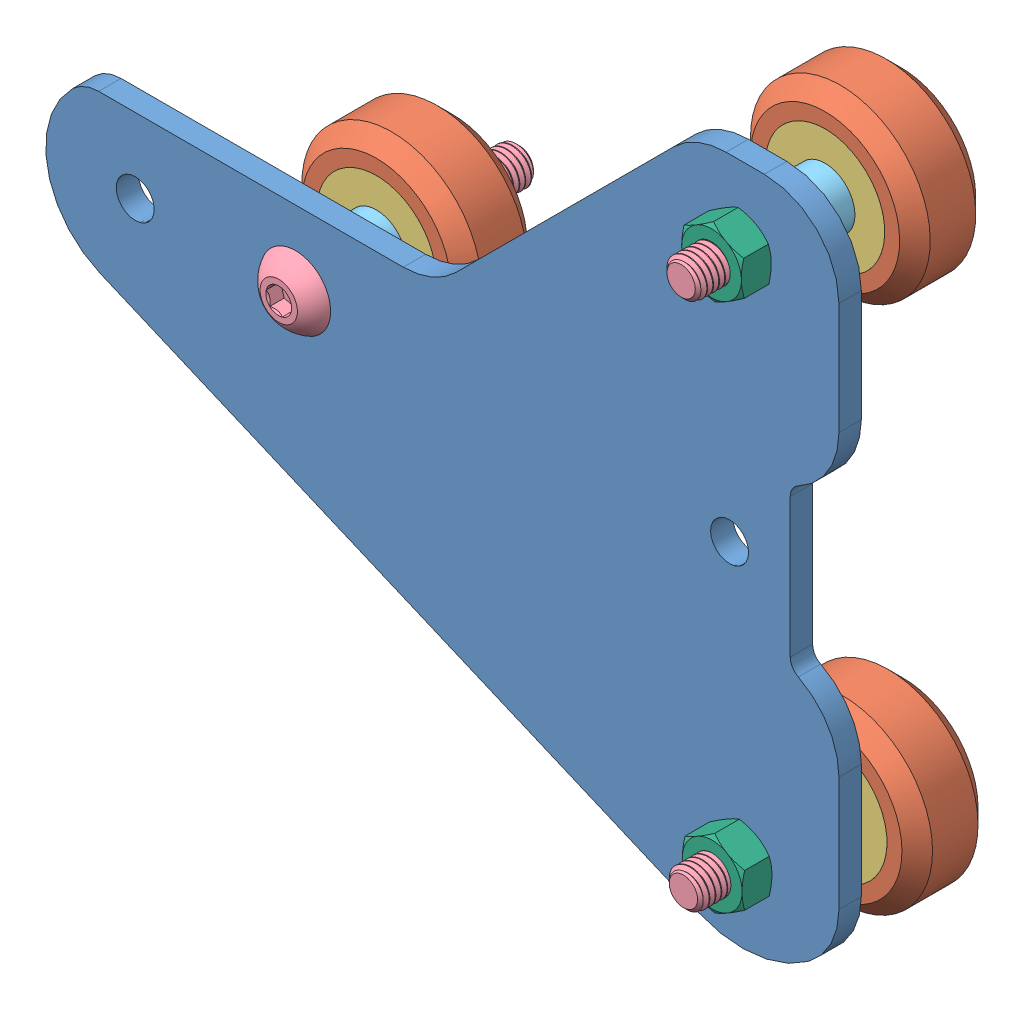
SolidWorks assembly Assembled_Z-Stent, configuration Default. Lengths in mm.
Overall size (110.68 104.98 29.88).
22 component instances, 6 part files, 8 mates.
Components (placement in the parent):
- Z Stent-2: Z Stent [Default] at origin size (106.35 91.34 3)
- roller_screw_assembly-1: roller_screw_assembly [Default] at (46.2218 63.5944 -12.95) x (0.760075 -0.649836 0) z (0 0 -1) size (24.1 24.1 20.97)
  - roller_rubber-1: roller_rubber [Default] at origin size (24.1 24.1 10.2)
  - Bearing for Roller-1: Bearing for Roller [Default] at (0 0 3.1) x (0.970422 -0.241413 0) z (0 0 1) size (16 16 2)
  - Bearing for Roller-2: Bearing for Roller [Default] at (0 0 -5.1) x (0.995973 0.089651 0) z (0 0 1) size (16 16 2)
  - 92095A211_Button Head Hex Drive Screw-1: 92095A211_Button Head Hex Drive Screw [92095A211] at (0 0 7.85) x (-0.966026 0.258445 0) z (0 0 1) size (9.5 9.5 17.99)
  - Roller Spacer-1: Roller Spacer [short] at (0 0 -12.95) x (0.816952 -0.576706 0) z (0 0 1) size (8 8 7.85)
- roller_screw_assembly-2: roller_screw_assembly [Default] at (46.2646 -7.409 -13.2145) x (0.760075 -0.649836 0) z (0 0 -1) size (24.1 24.1 20.97)
  - roller_rubber-1: roller_rubber [Default] at origin size (24.1 24.1 10.2)
  - Bearing for Roller-1: Bearing for Roller [Default] at (0 0 3.1) x (0.970422 -0.241413 0) z (0 0 1) size (16 16 2)
  - Bearing for Roller-2: Bearing for Roller [Default] at (0 0 -5.1) x (0.995973 0.089651 0) z (0 0 1) size (16 16 2)
  - 92095A211_Button Head Hex Drive Screw-1: 92095A211_Button Head Hex Drive Screw [92095A211] at (0 0 7.85) x (-0.966026 0.258445 0) z (0 0 1) size (9.5 9.5 17.99)
  - Roller Spacer-1: Roller Spacer [short] at (0 0 -12.95) x (0.816952 -0.576706 0) z (0 0 1) size (8 8 7.85)
- roller_screw_assembly-3: roller_screw_assembly [eccentric roller_3mm_gap] at (-13.9313 28.0966 -12.95) x (-0.021852 0.999761 0) z (0 0 1) size (24.1 24.1 23.47)
  - roller_rubber-1: roller_rubber [Default] at origin size (24.1 24.1 10.2)
  - Bearing for Roller-1: Bearing for Roller [Default] at (0 0 3.1) x (0.970422 -0.241413 0) z (0 0 1) size (16 16 2)
  - Bearing for Roller-2: Bearing for Roller [Default] at (0 0 -5.1) x (0.995973 0.089651 0) z (0 0 1) size (16 16 2)
  - 92095A211_Button Head Hex Drive Screw-1: 92095A211_Button Head Hex Drive Screw [92095A211] at (0 0 18.2) x (-0.966026 0.258445 0) z (0 0 1) size (9.5 9.5 17.99)
  - Roller Spacer-1: Roller Spacer [short] at (0 0 5.1) x (0.816952 -0.576706 0) z (0 0 1) size (8 8 7.85)
- 91828A241_18-8 Stainless Steel Hex Nut-1: 91828A241_18-8 Stainless Steel Hex Nut [91828A241] at (-13.9313 28.0966 -20.05) x (0.999999 0.001176 0) z (0 0 1) size (8 9.24 4.46)
- 91828A241_18-8 Stainless Steel Hex Nut-2: 91828A241_18-8 Stainless Steel Hex Nut [91828A241] at (46.2646 -7.409 5.3233) x (0.999999 0.001176 0) z (0 0 1) size (8 9.24 4.46)
- 91828A241_18-8 Stainless Steel Hex Nut-3: 91828A241_18-8 Stainless Steel Hex Nut [91828A241] at (46.2218 63.5944 5.3695) x (0.48508 0.87447 0) z (0 0 1) size (8 9.24 4.46)
Mates (geometry in assembly coordinates):
- Concentric1: concentric anti-aligned: circle of Z Stent-2; circle of roller_screw_assembly-2/Roller Spacer-1
- Concentric2: concentric anti-aligned: circle of Z Stent-2; circle of 91828A241_18-8 Stainless Steel Hex Nut-2
- Concentric5: concentric anti-aligned: circle of Z Stent-2; circle of roller_screw_assembly-1/Roller Spacer-1
- Coincident2: coincident anti-aligned: plane of Z Stent-2 through (-40.3202 33.0967 0) normal (0 0 -1); plane of roller_screw_assembly-1/Roller Spacer-1 through (46.2218 63.5944 0) normal (0 0 1)
- Concentric6: concentric anti-aligned: circle of Z Stent-2; circle of 91828A241_18-8 Stainless Steel Hex Nut-3
- Concentric8: concentric aligned: circle of Z Stent-2; circle of roller_screw_assembly-3/Roller Spacer-1
- Coincident7: coincident anti-aligned: plane of Z Stent-2 through (-40.3202 33.0967 0) normal (0 0 -1); plane of roller_screw_assembly-3/Roller Spacer-1 through (-13.9313 28.0966 0) normal (0 0 1)
- Coincident9: coincident anti-aligned: cone of roller_screw_assembly-3/Bearing for Roller-2; cone of 91828A241_18-8 Stainless Steel Hex Nut-1 through (-13.9313 28.0966 -18.05) axis (0 0 -1)
